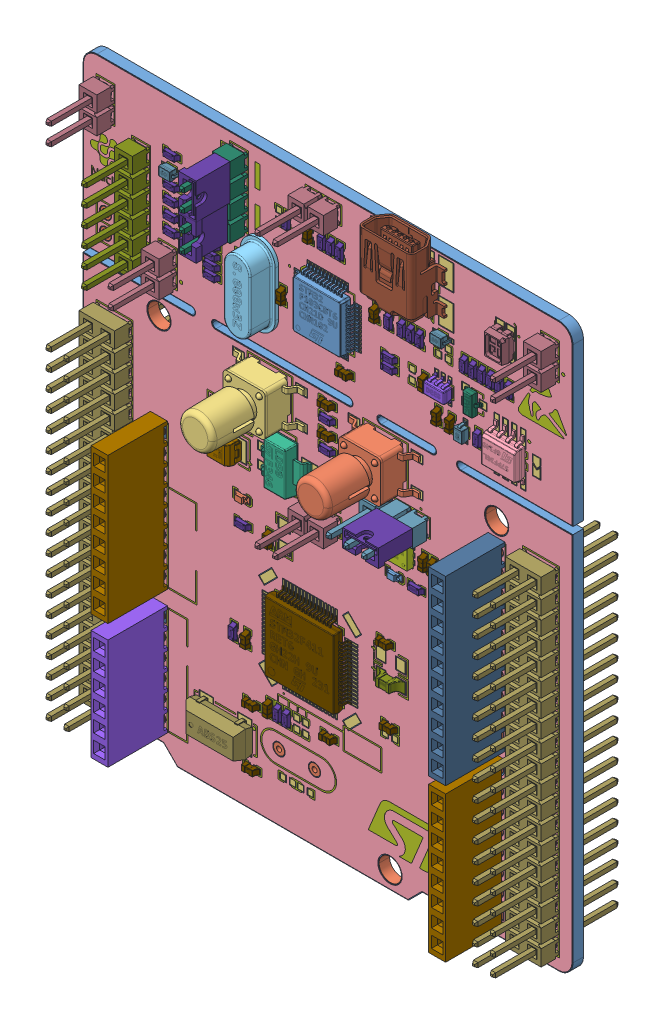
SolidWorks assembly NUCLEO-60-F401, configuration Default. Lengths in mm.
Overall size (70 83.97 20.27).
103 component instances, 38 part files, 0 mates.
Components (placement in the parent):
- NUCLEO-60-F401.STEP-1: NUCLEO-60-F401.STEP [Default] at origin size (70 83.97 20.27)
  - NUCLEO-F411RE_PCB_Varsay_lan.STEP-1: NUCLEO-F411RE_PCB_Varsay_lan.STEP [Default] at origin size (70 82.5 1.5)
  - NUCLEO-F411RE_PCB_HOLEs_Varsay_lan.STEP-1: NUCLEO-F411RE_PCB_HOLEs_Varsay_lan.STEP [Default] at origin size (65.28 79.87 1.57)
  - NUCLEO-F411RE_PCB_TOP_Pads_Varsay_lan.STEP-1: NUCLEO-F411RE_PCB_TOP_Pads_Varsay_lan.STEP [Default] at origin size (59.94 77.1 0.04)
  - NUCLEO-F411RE_PCB_TOP_Solder_Varsay_lan.STEP-1: NUCLEO-F411RE_PCB_TOP_Solder_Varsay_lan.STEP [Default] at origin size (69.8 82.3 0.05)
  - NUCLEO-F411RE_PCB_BOTTOM_Pads_Varsay_lan.STEP-1: NUCLEO-F411RE_PCB_BOTTOM_Pads_Varsay_lan.STEP [Default] at origin size (31.1 70.87 0.04)
  - NUCLEO-F411RE_PCB_BOTTOM_Solder_Varsay_lan.STEP-1: NUCLEO-F411RE_PCB_BOTTOM_Solder_Varsay_lan.STEP [Default] at origin size (69.8 82.3 0.04)
  - NUCLEO-F411RE_PCB_TOP_Overlay_Varsay_lan.STEP-1: NUCLEO-F411RE_PCB_TOP_Overlay_Varsay_lan.STEP [Default] at origin size (68.11 77.67 0.04)
  - SAMTEC_SSQ-106-01-G-S_for_NUCLEO_Varsay_lan.STEP-1: SAMTEC_SSQ-106-01-G-S_for_NUCLEO_Varsay_lan.STEP [Default] at (-33.02 8.89 0.785) x (0 1 0) z (1 0 0) size (15.75 11.15 2.41)
  - SAMTEC_SSQ-108-01-G-S_for_NUCLEO_Varsay_lan.STEP-1: SAMTEC_SSQ-108-01-G-S_for_NUCLEO_Varsay_lan.STEP [Default] at (-33.02 29.21 0.785) x (0 1 0) z (1 0 0) size (20.83 11.15 2.41)
  - SAMTEC_SSQ-108-01-G-S_for_NUCLEO_Varsay_lan.STEP-2: SAMTEC_SSQ-108-01-G-S_for_NUCLEO_Varsay_lan.STEP [Default] at (15.24 11.43 0.785) x (0 1 0) z (1 0 0) size (20.83 11.15 2.41)
  - SAMTEC_SSQ-110-01-G-S_for_NUCLEO_Varsay_lan.STEP-1: SAMTEC_SSQ-110-01-G-S_for_NUCLEO_Varsay_lan.STEP [Default] at (15.24 35.814 0.785) x (0 1 0) z (1 0 0) size (25.91 11.15 2.41)
  - MOLEX_0678038020_for_NUCLEO.STEP-1: MOLEX_0678038020_for_NUCLEO.STEP [Default] at (3.1721 75.2975 0.785) x (-1 0 0) z (0 1 0) size (9.9 4.95 9)
  - SAMTEC_TSW-119-07-T-D_for_NUCLEO_Varsay_lan.STEP-1: SAMTEC_TSW-119-07-T-D_for_NUCLEO_Varsay_lan.STEP [Default] at (-39.37 25.4 0.785) x (0 -1 0) z (-1 0 0) size (48.26 17.95 5.08)
  - SAMTEC_TSW-119-07-T-D_for_NUCLEO_Varsay_lan.STEP-2: SAMTEC_TSW-119-07-T-D_for_NUCLEO_Varsay_lan.STEP [Default] at (21.59 25.4 0.785) x (0 -1 0) z (-1 0 0) size (48.26 17.95 5.08)
  - SAMTEC_TSW-102-07-T-S_for_NUCLEO_Varsay_lan.STEP-1: SAMTEC_TSW-102-07-T-S_for_NUCLEO_Varsay_lan.STEP [Default] at (-40.64 74.93 0.785) x (0 1 0) z (1 0 0) size (5.08 10.92 2.54)
  - SAMTEC_TSW-102-07-T-S_for_NUCLEO_Varsay_lan.STEP-2: SAMTEC_TSW-102-07-T-S_for_NUCLEO_Varsay_lan.STEP [Default] at (-31.75 59.055 0.785) x (0 -1 0) z (-1 0 0) size (5.08 10.92 2.54)
  - SAMTEC_TSW-102-07-T-S_for_NUCLEO_Varsay_lan.STEP-3: SAMTEC_TSW-102-07-T-S_for_NUCLEO_Varsay_lan.STEP [Default] at (-9.525 77.47 0.785) x (1 0 0) z (0 -1 0) size (5.08 10.92 2.54)
  - SAMTEC_TSW-102-07-T-S_for_NUCLEO_Varsay_lan.STEP-4: SAMTEC_TSW-102-07-T-S_for_NUCLEO_Varsay_lan.STEP [Default] at (-9.525 38.735 0.785) x (1 0 0) z (0 -1 0) size (5.08 10.92 2.54)
  - SAMTEC_TSW-102-07-T-S_for_NUCLEO_Varsay_lan.STEP-5: SAMTEC_TSW-102-07-T-S_for_NUCLEO_Varsay_lan.STEP [Default] at (22.86 74.93 0.785) x (0 -1 0) z (-1 0 0) size (5.08 10.92 2.54)
  - SAMTEC_TSW-103-07-T-S_for_NUCLEO_Varsay_lan.STEP-1: SAMTEC_TSW-103-07-T-S_for_NUCLEO_Varsay_lan.STEP [Default] at (1.905 45.085 0.785) x (1 0 0) z (0 -1 0) size (7.62 10.92 2.54)
  - SAMTEC_TSW-104-07-T-S_for_NUCLEO_Varsay_lan.STEP-1: SAMTEC_TSW-104-07-T-S_for_NUCLEO_Varsay_lan.STEP [Default] at (-21.59 73.66 0.785) x (0 1 0) z (1 0 0) size (10.16 10.92 2.54)
  - SAMTEC_TSW-106-07-T-S_for_NUCLEO_Varsay_lan.STEP-1: SAMTEC_TSW-106-07-T-S_for_NUCLEO_Varsay_lan.STEP [Default] at (-35.56 64.77 0.785) x (0 1 0) z (1 0 0) size (15.24 10.92 2.54)
  - MOLEX_90059-0007.STEP-1: MOLEX_90059-0007.STEP [Default] at (-21.59 76.2 5.75) x (0 1 0) z (1 0 0) size (5.1 4.85 2.54)
  - MOLEX_90059-0007.STEP-2: MOLEX_90059-0007.STEP [Default] at (-21.59 71.12 5.75) x (0 -1 0) z (-1 0 0) size (5.1 4.85 2.54)
  - ST_STM32F411RET6_Varsay_lan.STEP-1: ST_STM32F411RET6_Varsay_lan.STEP [Default] at (-11.4265 21.5935 0.785) x (-1 0 0) z (0 0 -1) size (12 12 1.62)
  - ST_STM32F103CBT6_Varsay_lan.STEP-1: ST_STM32F103CBT6_Varsay_lan.STEP [Default] at (-8.89 64.77 0.785) x (1 0 0) z (0 -1 0) size (9 1.62 9)
  - ESWITCH_TL3301SPF160QGBLK_Varsay_lan.STEP-1: ESWITCH_TL3301SPF160QGBLK_Varsay_lan.STEP [Default] at (-0.635 50.8 0.785) x (0 -1 0) z (-1 0 0) size (6 10.7 10)
  - ESWITCH_TL3301SPF160QGBLU_Varsay_lan.STEP-1: ESWITCH_TL3301SPF160QGBLU_Varsay_lan.STEP [Default] at (-17.145 50.8 0.785) x (0 1 0) z (1 0 0) size (6 10.7 10)
  - ST_STS7PF30L_Varsay_lan.STEP-1: ST_STS7PF30L_Varsay_lan.STEP [Default] at (17.145 60.325 0.785) x (-1 0 0) z (0 1 0) size (4.9 1.77 6)
  - ABRACON_ABL-8.000MHZ-B2_Varsay_lan.STEP-1: ABRACON_ABL-8.000MHZ-B2_Varsay_lan.STEP [Default] at (-18.41 63.4908 0.785) x (0 -1 0) z (-1 0 0) size (11.5 5.59 5)
  - ST_LD1117S50TR_Varsay_lan.STEP-1: ST_LD1117S50TR_Varsay_lan.STEP [Default] at (-14.6685 43.18 0.785) x (0 -1 0) z (-1 0 0) size (6.5 1.92 7)
  - ST_LD39050PU33R_Varsay_lan.STEP-1: ST_LD39050PU33R_Varsay_lan.STEP [Default] at (1.905 40.64 0.785) x (0 1 0) z (1 0 0) size (3 1.02 3)
  - ST_LD3985M33R_Varsay_lan.STEP-1: ST_LD3985M33R_Varsay_lan.STEP [Default] at (7.62 63.5 0.785) x (1 0 0) z (0 -1 0) size (2.95 1.45 2.8)
  - KEMET_T491B106K025AT_Varsay_lan.STEP-1: KEMET_T491B106K025AT_Varsay_lan.STEP [Default] at (-22.86 41.275 0.785) x (0 -1 0) z (-1 0 0) size (2.8 1.92 3.5)
  - ST_STPS2L30A_Varsay_lan.STEP-1: ST_STPS2L30A_Varsay_lan.STEP [Default] at (-22.86 45.085 0.785) x (0 1 0) z (1 0 0) size (2.58 2.32 5.07)
  - KEMET_T491A106K006AT7280_Varsay_lan.STEP-1: KEMET_T491A106K006AT7280_Varsay_lan.STEP [Default] at (-8.255 43.053 0.785) x (1 0 0) z (0 -1 0) size (1.6 1.62 3.2)
  - ABRACON_ABS25-32.768KHZ-6-T_Varsay_lan.STEP-1: ABRACON_ABS25-32.768KHZ-6-T_Varsay_lan.STEP [Default] at (-23.495 6.35 0.785) x (1 0 0) z (0 -1 0) size (8 2.68 4)
  - LUMEX_SML-LX2835IGC-TR.STEP-1: LUMEX_SML-LX2835IGC-TR.STEP [Default] at (16.51 73.66 0.785) x (1 0 0) z (0 -1 0) size (2.7 1.8 3.5)
  - MOLEX_90059-0007.STEP-3: MOLEX_90059-0007.STEP [Default] at (3.175 45.085 5.75) x (-1 0 0) z (0 1 0) size (5.1 4.85 2.54)
  - ST_BAT60JFILM_Varsay_lan.STEP-1: ST_BAT60JFILM_Varsay_lan.STEP [Default] at (-31.115 71.12 0.785) x (0 -1 0) z (-1 0 0) size (1.28 1.19 2.5)
  - ST_BAT60JFILM_Varsay_lan.STEP-2: ST_BAT60JFILM_Varsay_lan.STEP [Default] at (7.62 69.85 0.785) x (0 -1 0) z (-1 0 0) size (1.28 1.19 2.5)
  - NXP_BC847B,215.STEP-1: NXP_BC847B,215.STEP [Default] at (12.065 64.135 0.785) x (0 -1 0) z (-1 0 0) size (2.9 1.1 2.43)
  - ST_BAT60JFILM_Varsay_lan.STEP-3: ST_BAT60JFILM_Varsay_lan.STEP [Default] at (10.795 59.69 0.785) x (1 0 0) z (0 -1 0) size (1.28 1.19 2.5)
  - YAGEO_CC0805KKX7R7BB225.STEP-1: YAGEO_CC0805KKX7R7BB225.STEP [Default] at (0.127 23.495 0.785) x (0 -1 0) z (-1 0 0) size (1.58 1.29 4.07)
  - YAGEO_RC0603JR-070RL.STEP-1: YAGEO_RC0603JR-070RL.STEP [Default] at (17.145 67.945 0.785) x (1 0 0) z (0 -1 0) size (0.8 0.6 2.18)
  - YAGEO_RC0603JR-070RL.STEP-2: YAGEO_RC0603JR-070RL.STEP [Default] at (15.875 67.945 0.785) x (1 0 0) z (0 -1 0) size (0.8 0.6 2.18)
  - YAGEO_RC0603JR-070RL.STEP-3: YAGEO_RC0603JR-070RL.STEP [Default] at (14.605 67.945 0.785) x (1 0 0) z (0 -1 0) size (0.8 0.6 2.18)
  - YAGEO_RC0603JR-070RL.STEP-4: YAGEO_RC0603JR-070RL.STEP [Default] at (13.335 67.945 0.785) x (1 0 0) z (0 -1 0) size (0.8 0.6 2.18)
  - YAGEO_RC0603JR-070RL.STEP-5: YAGEO_RC0603JR-070RL.STEP [Default] at (12.065 67.945 0.785) x (1 0 0) z (0 -1 0) size (0.8 0.6 2.18)
  - YAGEO_RC0603JR-070RL.STEP-6: YAGEO_RC0603JR-070RL.STEP [Default] at (10.795 67.945 0.785) x (1 0 0) z (0 -1 0) size (0.8 0.6 2.18)
  - YAGEO_RC0603JR-070RL.STEP-7: YAGEO_RC0603JR-070RL.STEP [Default] at (12.7 59.7535 0.785) x (1 0 0) z (0 -1 0) size (0.8 0.6 2.18)
  - YAGEO_RC0603JR-070RL.STEP-8: YAGEO_RC0603JR-070RL.STEP [Default] at (4.445 67.945 0.785) x (1 0 0) z (0 -1 0) size (0.8 0.6 2.18)
  - YAGEO_RC0603JR-070RL.STEP-9: YAGEO_RC0603JR-070RL.STEP [Default] at (3.175 67.945 0.785) x (1 0 0) z (0 -1 0) size (0.8 0.6 2.18)
  - YAGEO_RC0603JR-070RL.STEP-10: YAGEO_RC0603JR-070RL.STEP [Default] at (1.905 67.945 0.785) x (1 0 0) z (0 -1 0) size (0.8 0.6 2.18)
  - YAGEO_RC0603JR-070RL.STEP-11: YAGEO_RC0603JR-070RL.STEP [Default] at (0 67.945 0.785) x (1 0 0) z (0 -1 0) size (0.8 0.6 2.18)
  - YAGEO_RC0603JR-070RL.STEP-12: YAGEO_RC0603JR-070RL.STEP [Default] at (-6.985 73.025 0.785) x (1 0 0) z (0 -1 0) size (0.8 0.6 2.18)
  - YAGEO_RC0603JR-070RL.STEP-13: YAGEO_RC0603JR-070RL.STEP [Default] at (-8.255 73.025 0.785) x (1 0 0) z (0 -1 0) size (0.8 0.6 2.18)
  - YAGEO_RC0603JR-070RL.STEP-14: YAGEO_RC0603JR-070RL.STEP [Default] at (-9.525 73.025 0.785) x (1 0 0) z (0 -1 0) size (0.8 0.6 2.18)
  - YAGEO_RC0603JR-070RL.STEP-15: YAGEO_RC0603JR-070RL.STEP [Default] at (-14.605 73.025 0.785) x (1 0 0) z (0 -1 0) size (0.8 0.6 2.18)
  - YAGEO_RC0603JR-070RL.STEP-16: YAGEO_RC0603JR-070RL.STEP [Default] at (-31.115 73.025 0.785) x (0 -1 0) z (-1 0 0) size (0.8 0.6 2.18)
  - YAGEO_RC0603JR-070RL.STEP-17: YAGEO_RC0603JR-070RL.STEP [Default] at (-31.115 69.215 0.785) x (0 -1 0) z (-1 0 0) size (0.8 0.6 2.18)
  - YAGEO_RC0603JR-070RL.STEP-18: YAGEO_RC0603JR-070RL.STEP [Default] at (-31.115 67.31 0.785) x (0 -1 0) z (-1 0 0) size (0.8 0.6 2.18)
  - YAGEO_RC0603JR-070RL.STEP-19: YAGEO_RC0603JR-070RL.STEP [Default] at (-31.115 65.405 0.785) x (0 -1 0) z (-1 0 0) size (0.8 0.6 2.18)
  - YAGEO_RC0603JR-070RL.STEP-20: YAGEO_RC0603JR-070RL.STEP [Default] at (-31.115 63.5 0.785) x (0 -1 0) z (-1 0 0) size (0.8 0.6 2.18)
  - YAGEO_RC0603JR-070RL.STEP-21: YAGEO_RC0603JR-070RL.STEP [Default] at (-25.4 64.77 0.785) x (0 -1 0) z (-1 0 0) size (0.8 0.6 2.18)
  - YAGEO_RC0603JR-070RL.STEP-22: YAGEO_RC0603JR-070RL.STEP [Default] at (-25.4 63.5 0.785) x (0 -1 0) z (-1 0 0) size (0.8 0.6 2.18)
  - YAGEO_RC0603JR-070RL.STEP-23: YAGEO_RC0603JR-070RL.STEP [Default] at (-25.4 62.23 0.785) x (0 -1 0) z (-1 0 0) size (0.8 0.6 2.18)
  - YAGEO_RC0603JR-070RL.STEP-24: YAGEO_RC0603JR-070RL.STEP [Default] at (-25.4 60.96 0.785) x (0 -1 0) z (-1 0 0) size (0.8 0.6 2.18)
  - YAGEO_RC0603JR-070RL.STEP-25: YAGEO_RC0603JR-070RL.STEP [Default] at (-15.875 11.43 0.785) x (1 0 0) z (0 -1 0) size (0.8 0.6 2.18)
  - YAGEO_RC0603JR-070RL.STEP-26: YAGEO_RC0603JR-070RL.STEP [Default] at (-14.605 11.43 0.785) x (1 0 0) z (0 -1 0) size (0.8 0.6 2.18)
  - YAGEO_RC0603JR-070RL.STEP-27: YAGEO_RC0603JR-070RL.STEP [Default] at (-22.225 18.415 0.785) x (1 0 0) z (0 -1 0) size (0.8 0.6 2.18)
  - YAGEO_RC0603JR-070RL.STEP-28: YAGEO_RC0603JR-070RL.STEP [Default] at (-20.955 32.385 0.785) x (0 -1 0) z (-1 0 0) size (0.8 0.6 2.18)
  - YAGEO_RC0603JR-070RL.STEP-29: YAGEO_RC0603JR-070RL.STEP [Default] at (-8.89 51.435 0.785) x (0 -1 0) z (-1 0 0) size (0.8 0.6 2.18)
  - YAGEO_RC0603JR-070RL.STEP-30: YAGEO_RC0603JR-070RL.STEP [Default] at (-8.89 47.625 0.785) x (0 -1 0) z (-1 0 0) size (0.8 0.6 2.18)
  - YAGEO_RC0603JR-070RL.STEP-31: YAGEO_RC0603JR-070RL.STEP [Default] at (3.81 36.83 0.785) x (0 -1 0) z (-1 0 0) size (0.8 0.6 2.18)
  - YAGEO_RC0603JR-070RL.STEP-32: YAGEO_RC0603JR-070RL.STEP [Default] at (0 63.5 0.785) x (0 -1 0) z (-1 0 0) size (0.8 0.6 2.18)
  - YAGEO_RC0603JR-070RL.STEP-33: YAGEO_RC0603JR-070RL.STEP [Default] at (0 62.23 0.785) x (0 -1 0) z (-1 0 0) size (0.8 0.6 2.18)
  - YAGEO_CC0603KRX7R7BB104.STEP-1: YAGEO_CC0603KRX7R7BB104.STEP [Default] at (-11.43 73.025 0.785) x (1 0 0) z (0 -1 0) size (0.8 0.81 2.21)
  - YAGEO_CC0603KRX7R7BB104.STEP-2: YAGEO_CC0603KRX7R7BB104.STEP [Default] at (-1.905 67.945 0.785) x (1 0 0) z (0 -1 0) size (0.8 0.81 2.21)
  - YAGEO_CC0603KRX7R7BB104.STEP-3: YAGEO_CC0603KRX7R7BB104.STEP [Default] at (5.08 62.865 0.785) x (1 0 0) z (0 -1 0) size (0.8 0.81 2.21)
  - YAGEO_CC0603KRX7R7BB104.STEP-4: YAGEO_CC0603KRX7R7BB104.STEP [Default] at (6.985 59.69 0.785) x (1 0 0) z (0 -1 0) size (0.8 0.81 2.21)
  - YAGEO_CC0603KRX7R7BB104.STEP-5: YAGEO_CC0603KRX7R7BB104.STEP [Default] at (8.89 59.69 0.785) x (1 0 0) z (0 -1 0) size (0.8 0.81 2.21)
  - YAGEO_CC0603KRX7R7BB104.STEP-6: YAGEO_CC0603KRX7R7BB104.STEP [Default] at (-21.59 62.23 0.785) x (1 0 0) z (0 -1 0) size (0.8 0.81 2.21)
  - YAGEO_CC0603KRX7R7BB104.STEP-7: YAGEO_CC0603KRX7R7BB104.STEP [Default] at (-21.59 64.77 0.785) x (1 0 0) z (0 -1 0) size (0.8 0.81 2.21)
  - YAGEO_CC0603KRX7R7BB104.STEP-8: YAGEO_CC0603KRX7R7BB104.STEP [Default] at (-15.24 63.5 0.785) x (1 0 0) z (0 -1 0) size (0.8 0.81 2.21)
  - YAGEO_CC0603KRX7R7BB104.STEP-9: YAGEO_CC0603KRX7R7BB104.STEP [Default] at (-6.35 58.42 0.785) x (0 -1 0) z (-1 0 0) size (0.8 0.81 2.21)
  - YAGEO_CC0603KRX7R7BB104.STEP-10: YAGEO_CC0603KRX7R7BB104.STEP [Default] at (-8.89 53.34 0.785) x (0 -1 0) z (-1 0 0) size (0.8 0.81 2.21)
  - YAGEO_CC0603KRX7R7BB104.STEP-11: YAGEO_CC0603KRX7R7BB104.STEP [Default] at (-8.89 49.53 0.785) x (0 -1 0) z (-1 0 0) size (0.8 0.81 2.21)
  - YAGEO_CC0603KRX7R7BB104.STEP-12: YAGEO_CC0603KRX7R7BB104.STEP [Default] at (-2.54 40.64 0.785) x (1 0 0) z (0 -1 0) size (0.8 0.81 2.21)
  - YAGEO_CC0603KRX7R7BB104.STEP-13: YAGEO_CC0603KRX7R7BB104.STEP [Default] at (-1.27 40.64 0.785) x (1 0 0) z (0 -1 0) size (0.8 0.81 2.21)
  - YAGEO_CC0603KRX7R7BB104.STEP-14: YAGEO_CC0603KRX7R7BB104.STEP [Default] at (5.08 40.64 0.785) x (1 0 0) z (0 -1 0) size (0.8 0.81 2.21)
  - YAGEO_CC0603KRX7R7BB104.STEP-15: YAGEO_CC0603KRX7R7BB104.STEP [Default] at (6.35 40.64 0.785) x (1 0 0) z (0 -1 0) size (0.8 0.81 2.21)
  - YAGEO_CC0603KRX7R7BB104.STEP-16: YAGEO_CC0603KRX7R7BB104.STEP [Default] at (-0.6033 27.94 0.785) x (0 -1 0) z (-1 0 0) size (0.8 0.81 2.21)
  - YAGEO_CC0603KRX7R7BB104.STEP-17: YAGEO_CC0603KRX7R7BB104.STEP [Default] at (-17.145 32.385 0.785) x (1 0 0) z (0 -1 0) size (0.8 0.81 2.21)
  - YAGEO_CC0603KRX7R7BB104.STEP-18: YAGEO_CC0603KRX7R7BB104.STEP [Default] at (-20.32 18.415 0.785) x (1 0 0) z (0 -1 0) size (0.8 0.81 2.21)
  - YAGEO_CC0603KRX7R7BB104.STEP-19: YAGEO_CC0603KRX7R7BB104.STEP [Default] at (-17.145 11.43 0.785) x (1 0 0) z (0 -1 0) size (0.8 0.81 2.21)
  - YAGEO_CC0603KRX7R7BB104.STEP-20: YAGEO_CC0603KRX7R7BB104.STEP [Default] at (0 17.78 0.785) x (0 -1 0) z (-1 0 0) size (0.8 0.81 2.21)
  - YAGEO_CC0603KRX7R7BB104.STEP-21: YAGEO_CC0603KRX7R7BB104.STEP [Default] at (-8.636 12.192 0.785) x (0 -1 0) z (-1 0 0) size (0.8 0.81 2.21)
  - YAGEO_CC0603KRX7R7BB104.STEP-22: YAGEO_CC0603KRX7R7BB104.STEP [Default] at (-19.685 2.794 0.785) x (0 -1 0) z (-1 0 0) size (0.8 0.81 2.21)
  - YAGEO_CC0603KRX7R7BB104.STEP-23: YAGEO_CC0603KRX7R7BB104.STEP [Default] at (-19.685 10.795 0.785) x (0 -1 0) z (-1 0 0) size (0.8 0.81 2.21)
  - LUMEX_SML-LX0603SRW-TR.STEP-1: LUMEX_SML-LX0603SRW-TR.STEP [Default] at (0.635 36.83 0.785) x (1 0 0) z (0 -1 0) size (2.16 0.61 0.8)
  - LUMEX_SML-LX0603GW-TR.STEP-1: LUMEX_SML-LX0603GW-TR.STEP [Default] at (-21.1455 35.5597 0.785) x (1 0 0) z (0 -1 0) size (2.16 0.61 0.8)
